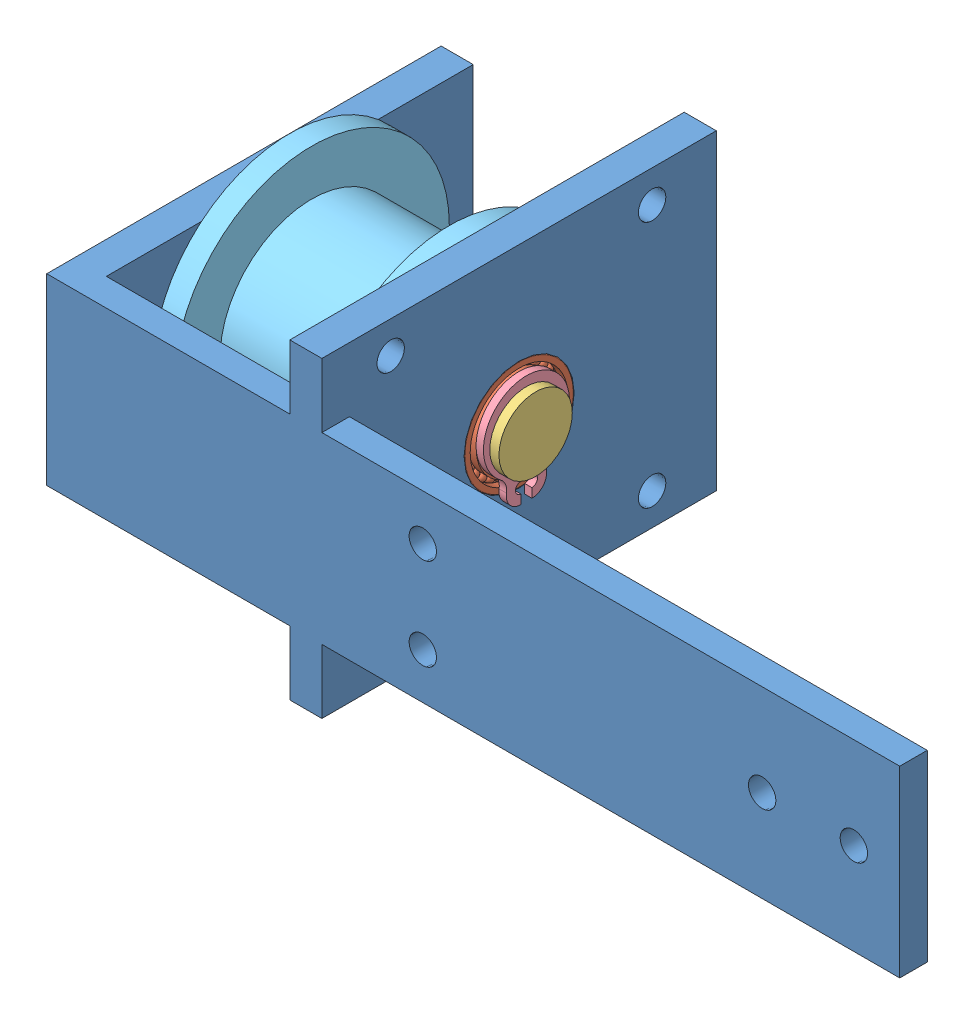
SolidWorks assembly 卷帘滑轮-安装, configuration 默认. Lengths in mm.
Overall size (94.8 34 43).
7 component instances, 5 part files, 12 mates.
Components (placement in the parent):
- 卷帘安装架-1: 卷帘安装架 [默认] at (119.4297 11.8196 18.5) size (93 34 43)
- deep groove ball bearings gb-1: deep groove ball bearings gb [Rolling bearings 617-8 GB 276-94] at (37.6797 11.6738 0) size (2.5 12 12)
- deep groove ball bearings gb-2: deep groove ball bearings gb [Rolling bearings 617-8 GB 276-94] at (65.1797 11.6738 0) size (2.5 12 12)
- 滑轮轴-1: 滑轮轴 [默认] at (51.4297 11.6738 0) x (0 0 1) z (-1 0 0) size (9.5 9.5 33.6)
- circlips for shaft--type a small gb-2: circlips for shaft--type a small gb [GB_CONNECTING_PIECE_RING_RRA 8] at (66.4297 12.0038 0) x (0 0 1) z (-1 0 0) size (9.38 11.87 0.8)
- circlips for shaft--type a small gb-3: circlips for shaft--type a small gb [GB_CONNECTING_PIECE_RING_RRA 8] at (36.4297 12.0038 0) x (0 0 -1) z (1 0 0) size (9.38 11.87 0.8)
- 滑轮 - 卷帘-1: 滑轮 - 卷帘 [默认] at (41.4297 11.6738 0) x (0 -1 0) z (0 0 1) size (30 20 30)
Mates (geometry in assembly coordinates):
- 同心11: concentric aligned: cylinder of 卷帘安装架-1 through (74.4297 11.6738 0) axis (-1 0 0) radius 6; cylinder of deep groove ball bearings gb-1 through (30.7083 11.6738 0) axis (-1 0 0) radius 4
- 重合11: coincident anti-aligned: plane of 卷帘安装架-1 through (38.9297 11.6738 0) normal (-1 0 0); plane of deep groove ball bearings gb-1 through (38.9297 15.6738 0) normal (1 0 0)
- 同心21: concentric aligned: cylinder of 卷帘安装架-1 through (74.4297 11.6738 0) axis (-1 0 0) radius 6; cylinder of deep groove ball bearings gb-2 through (58.2083 11.6738 0) axis (-1 0 0) radius 4
- 重合21: coincident anti-aligned: plane of 卷帘安装架-1 through (63.9297 11.6738 0) normal (1 0 0); plane of deep groove ball bearings gb-2 through (63.9297 16.3405 0) normal (-1 0 0)
- 同心31: concentric anti-aligned: cylinder of deep groove ball bearings gb-1 through (30.7083 11.6738 0) axis (-1 0 0) radius 4; cylinder of 滑轮轴-1 through (34.6297 11.6738 0) axis (1 0 0) radius 4
- 同心61: concentric anti-aligned: cylinder of 滑轮轴-1 through (34.6297 11.6738 0) axis (1 0 0) radius 4; cylinder of 滑轮 - 卷帘-1 through (61.4297 11.6738 0) axis (-1 0 0) radius 4
- 重合61: coincident aligned: plane of 卷帘安装架-1 through (51.4297 11.8196 18.5) normal (1 0 0); plane of 滑轮 - 卷帘-1
- 重合81: coincident aligned: plane of deep groove ball bearings gb-1 through (36.4297 16.3405 0) normal (-1 0 0); plane of 滑轮轴-1 through (36.4297 15.6738 0) normal (-1 0 0)
- 同心71: concentric aligned: cylinder of 滑轮轴-1 through (70.2297 11.6738 0) axis (1 0 0) radius 3.7; cylinder of circlips for shaft--type a small gb-3 through (35.6297 11.6738 0) axis (1 0 0) radius 3.7
- 重合91: coincident anti-aligned: plane of 滑轮轴-1 through (36.4297 15.6738 0) normal (-1 0 0); plane of circlips for shaft--type a small gb-3 through (36.4297 6.4228 0.6) normal (1 0 0)
- 同心8: concentric anti-aligned: cylinder of 滑轮轴-1 through (70.2297 11.6738 0) axis (1 0 0) radius 3.7; cylinder of circlips for shaft--type a small gb-2 through (67.2297 11.6738 0) axis (-1 0 0) radius 3.7
- 重合10: coincident anti-aligned: plane of 滑轮轴-1 through (66.4297 15.6738 0) normal (1 0 0); plane of circlips for shaft--type a small gb-2 through (66.4297 6.4228 -0.6) normal (-1 0 0)
